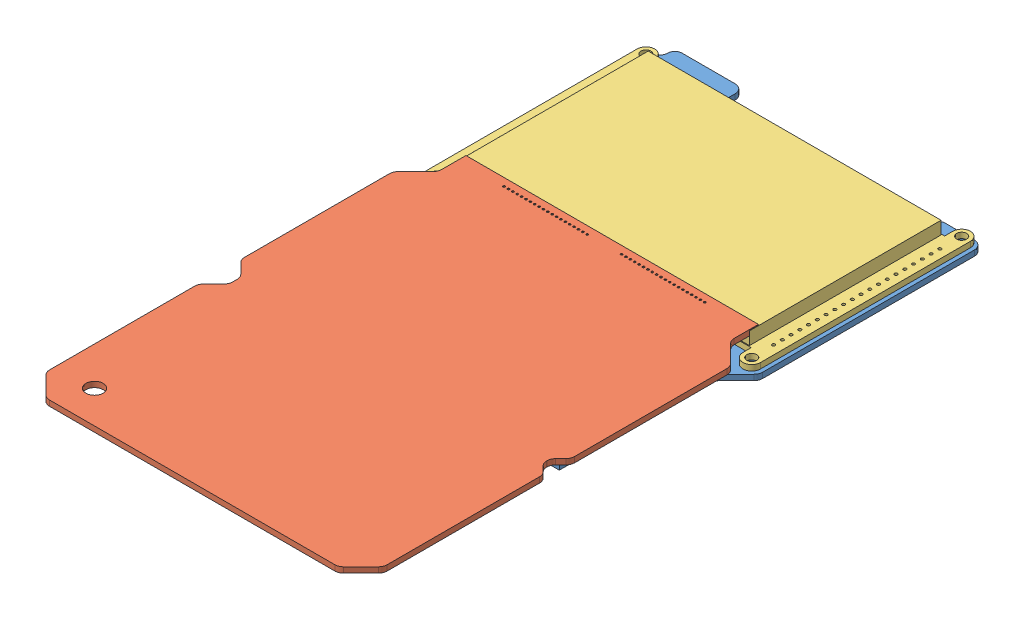
SolidWorks assembly Mockup Lineup, configuration Default. Lengths in mm.
Overall size (99 9.7 184.64).
3 component instances, 3 part files, 6 mates.
Components (placement in the parent):
- mainboard mock-1: mainboard mock [Default] at (37.8328 66.1251 62.7326) size (99 4.1 121.09)
- Switchboard Mock V2.5-1: Switchboard Mock V2.5 [Default] at (37.8328 71.7278 181.287) size (98 1.6 121.92)
- Adafruit Display-1: Adafruit Display [Default] at (37.8328 67.7251 34.2126) size (96.75 7.87 66.04)
Mates (geometry in assembly coordinates):
- Coincident1: coincident anti-aligned: plane of mainboard mock-1 through (37.8328 67.7251 62.7326) normal (0 1 0); plane of Adafruit Display-1 through (-8.0015 67.7251 3.7326) normal (0 -1 0)
- Concentric1: concentric aligned: cylinder of mainboard mock-1 through (-8.0015 67.7251 3.7326) axis (0 -1 0) radius 1.5; cylinder of Adafruit Display-1 through (-8.0015 69.3507 3.7326) axis (0 -1 0) radius 1.4605
- Concentric2: concentric anti-aligned: circle of mainboard mock-1; cylinder of Adafruit Display-1 through (83.6671 69.3507 3.7326) axis (0 -1 0) radius 1.4605
- Parallel2: parallel: plane of mainboard mock-1 through (37.8328 67.7251 62.7326) normal (0 1 0); plane of Switchboard Mock V2.5-1 through (37.8328 71.7278 181.287) normal (0 -1 0)
- Coincident5: coincident: plane of mainboard mock-1 through (73.8328 67.7251 62.7326) normal (0 0 -1); line of Switchboard Mock V2.5-1 through (79.8776 71.7278 62.7326) axis (-1 0 0)
- Width1: width anti-aligned: plane of Switchboard Mock V2.5-1 through (-4.6263 73.3278 181.287) normal (-1 0 0); plane of Adafruit Display-1 through (80.2918 73.3278 181.287) normal (1 0 0); plane of Switchboard Mock V2.5-1 through (86.2071 69.3507 3.7326) normal (1 0 0); plane of Adafruit Display-1 through (-10.5415 69.3507 3.7326) normal (-1 0 0)
